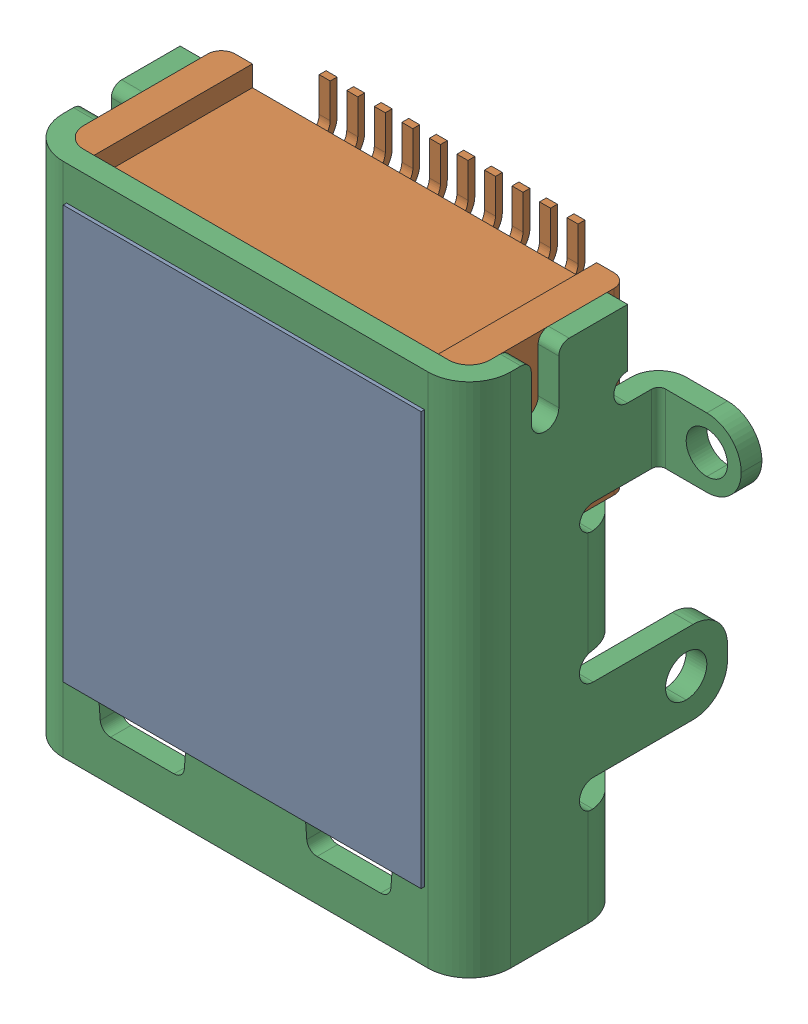
SolidWorks assembly J2, configuration Défaut. Lengths in mm.
Overall size (8.9 7.5 3.8).
3 component instances, 1 part files, 0 mates.
Components (placement in the parent):
- HDMI-101L-1: HDMI-101L [Défaut] at (36.05 -35.7354 -1.6) x (1 0 0) z (0 0 1) size (8.9 7.5 3.8)
  - 3767e841d01a442b9ab53d6dc2195e1f.step-1: 3767e841d01a442b9ab53d6dc2195e1f.step [Défaut] at (2.9312 -5.6922 1.6) size (8.9 7.5 3.8)
    - COMPOUND.step_1809-1: COMPOUND.step_1809 [Défaut] at origin size (8.9 7.5 3.8)
